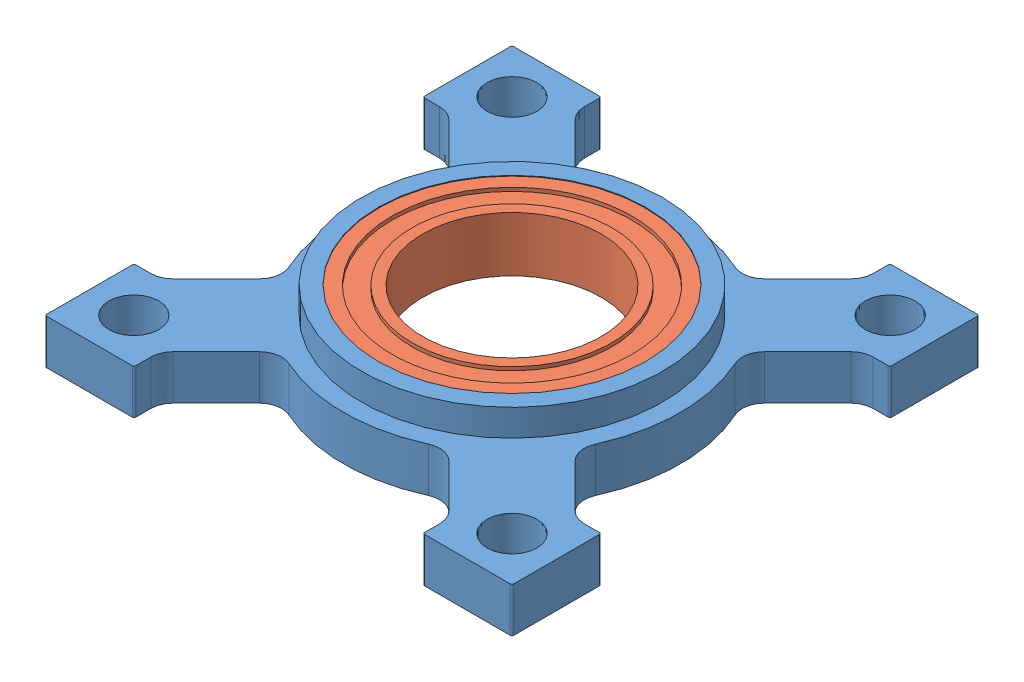
SolidWorks assembly 535118 assembly1, configuration Predeterminado. Lengths in mm.
Overall size (33.27 5.08 33.27).
2 component instances, 2 part files, 0 mates.
Components (placement in the parent):
- 535118-1: 535118 [Predeterminado] at (4.5754 14.638 29.8068) size (33.27 5.08 33.27)
- .5 x .75 non flanged bearing-1: .5 x .75 non flanged bearing [Predeterminado] at (4.5754 15.7556 29.8068) x (0.910445 0 -0.413629) z (0.413629 0 0.910445) size (19.05 3.91 19.05)
